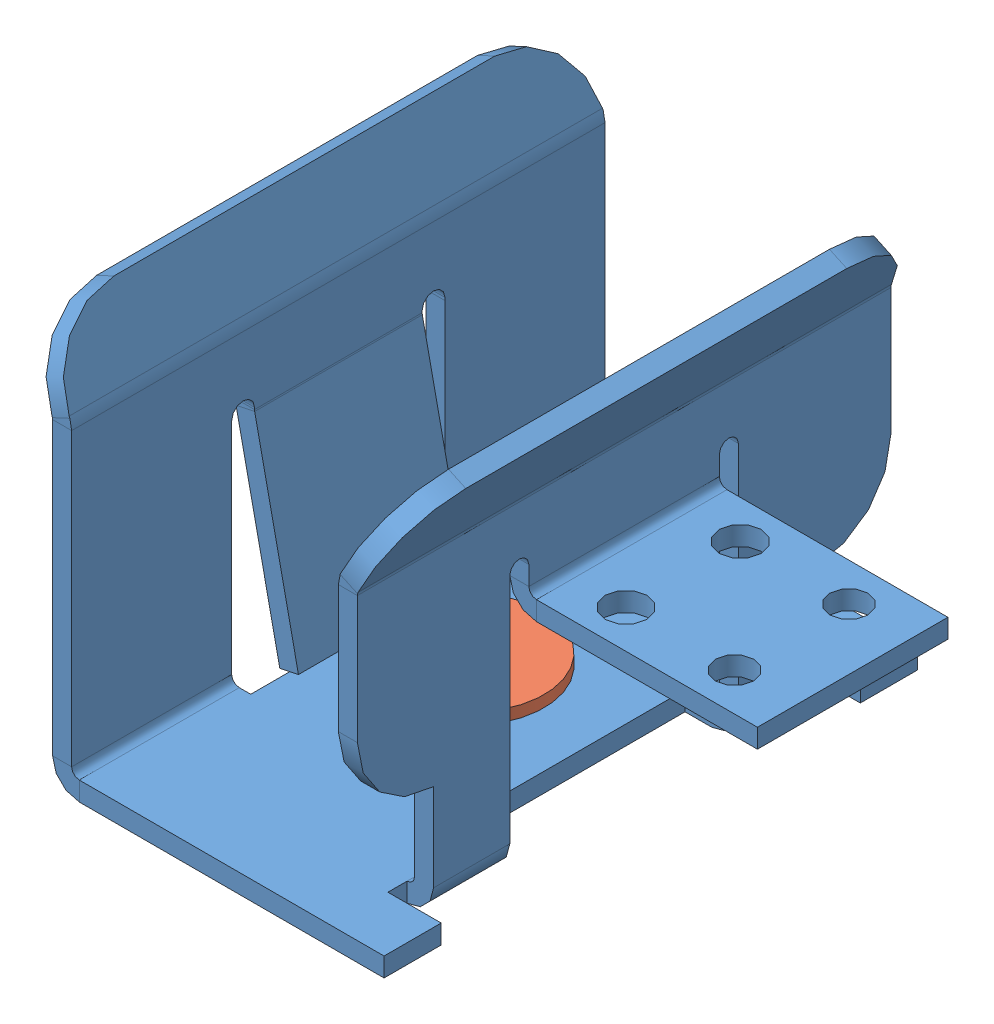
SolidWorks assembly B24-4C(Default-_flexible1), configuration Default. Lengths in mm.
Overall size (74.23 52.06 70.05).
2 component instances, 2 part files, 0 mates.
Components (placement in the parent):
- G2317(Default)-1: G2317(Default) [Default] at (-228.8356 13.2387 64.3644) x (1 0 0) z (0 1 0) size (74.23 70.05 52.06)
- G3002-1: G3002 [Default] at (-228.8356 19.4387 64.3644) x (0.930437 0 -0.366451) z (0.366451 0 0.930437) size (19 1.5 19)
